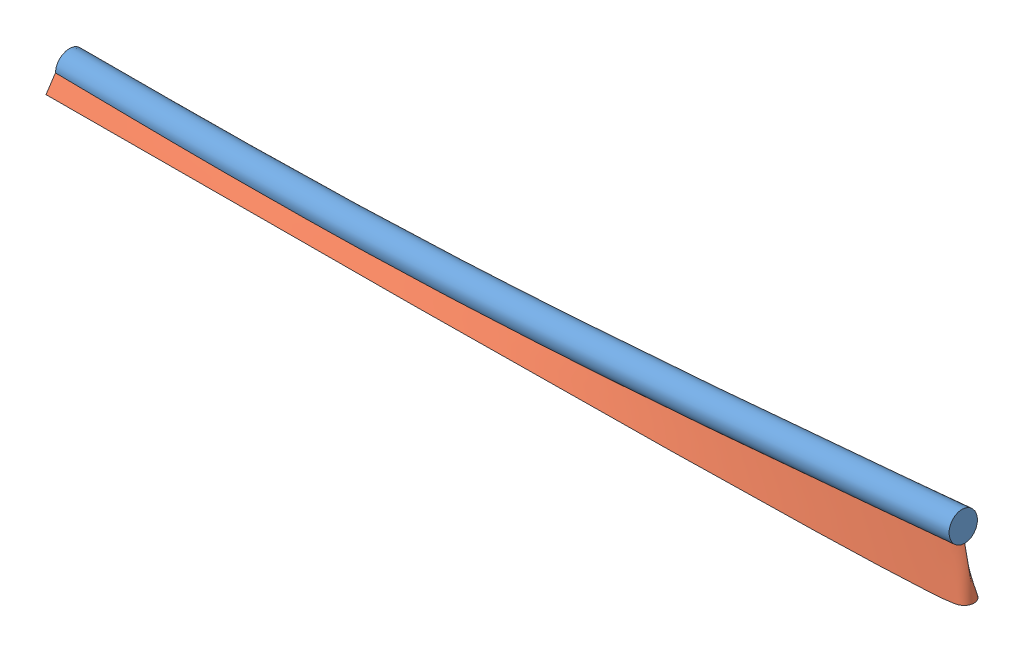
SolidWorks assembly ElevatorRodFairing, configuration Default. Lengths in mm.
Overall size (96.14 7.99 5.01).
2 component instances, 2 part files, 3 mates.
Components (placement in the parent):
- ElevatorRodGuide-1: ElevatorRodGuide [Default] at origin size (94.99 7.99 3)
- ElevatorRodFairing-1: ElevatorRodFairing [Default] at origin size (96.14 6.52 5.01)
Mates (geometry in assembly coordinates):
- Coincident2: coincident aligned: plane of ElevatorRodGuide-1 through (0 0 0) normal (0 0 1); plane of assembly through (0 0 0) normal (0 0 1)
- Coincident3: coincident aligned: plane of ElevatorRodGuide-1 through (0 0 0) normal (0 1 0); plane of assembly through (0 0 0) normal (0 1 0)
- Coincident4: coincident aligned: plane of ElevatorRodGuide-1 through (0 0 0) normal (1 0 0); plane of assembly through (0 0 0) normal (1 0 0)
